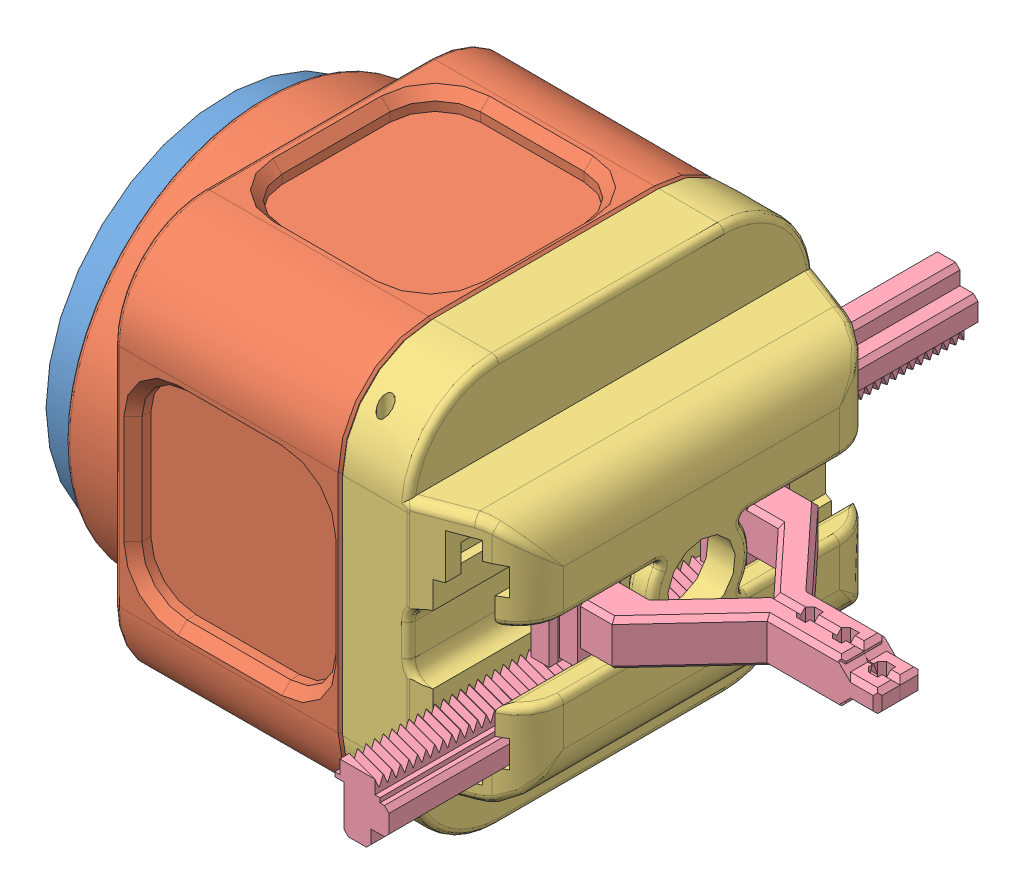
SolidWorks assembly grip-tool-model, configuration Default. Lengths in mm.
Overall size (149.24 90 130.5).
5 component instances, 4 part files, 9 mates.
Components (placement in the parent):
- connector imitation-2: connector imitation [Default] at origin size (10 80 80)
- case_link_2-1: case_link_2 [Default] at (8.24 0 0) x (0 0 -1) z (1 0 0) size (90 90 62)
- holder_link_2-1: holder_link_2 [Default] at (70.24 0 0) x (0 1 0) z (1 0 0) size (90 90.95 35)
- grip_link_3-1: grip_link_3 [Default] at (94.24 -16.5 65.25) x (0 0 -1) z (0 -1 0) size (90 62 32.75)
- grip_link_3-2: grip_link_3 [Default] at (94.24 16.5 -65.25) x (0 0 1) z (0 1 0) size (90 62 32.75)
Mates (geometry in assembly coordinates):
- Концентричный1: concentric aligned: cylinder of connector imitation-2 through (10 0 0) axis (-1 0 0) radius 40; cylinder of case_link_2-1 through (20.24 0 0) axis (-1 0 0) radius 40
- Расстояние1: distance = 8.24 mm aligned: plane of case_link_2-1 through (8.24 0 0) normal (-1 0 0); plane of connector imitation-2 through (0 0 0) normal (-1 0 0)
- Совпадение2: coincident anti-aligned: plane of case_link_2-1 through (70.24 -25 -25) normal (1 0 0); plane of holder_link_2-1 through (70.24 25 -25) normal (-1 0 0)
- Совпадение3: coincident aligned: plane of case_link_2-1 through (25.24 25 45) normal (0 0 1); plane of holder_link_2-1 through (80.24 25 45) normal (0 0 1)
- Совпадение4: coincident aligned: plane of case_link_2-1 through (25.24 45 25) normal (0 1 0); plane of holder_link_2-1 through (80.24 45 -25) normal (0 1 0)
- Совпадение5: coincident anti-aligned: plane of connector imitation-2 through (0 0 0) normal (0 0 1); plane of case_link_2-1 through (8.24 0 0) normal (0 0 -1)
- Совпадение6: coincident anti-aligned: plane of holder_link_2-1 through (91.24 -19.5 -45) normal (1 0 0); plane of grip_link_3-1 through (91.24 -23.5 -12.75) normal (-1 0 0)
- Совпадение7: coincident anti-aligned: plane of holder_link_2-1 through (91.24 -23.5 -45) normal (0 1 0); plane of grip_link_3-1 through (97.24 -23.5 -12.75) normal (0 -1 0)
- Совпадение8: coincident anti-aligned: plane of grip_link_3-1 through (121.24 -5 0) normal (0 0 1); plane of grip_link_3-2 through (121.24 5 0) normal (0 0 -1)
